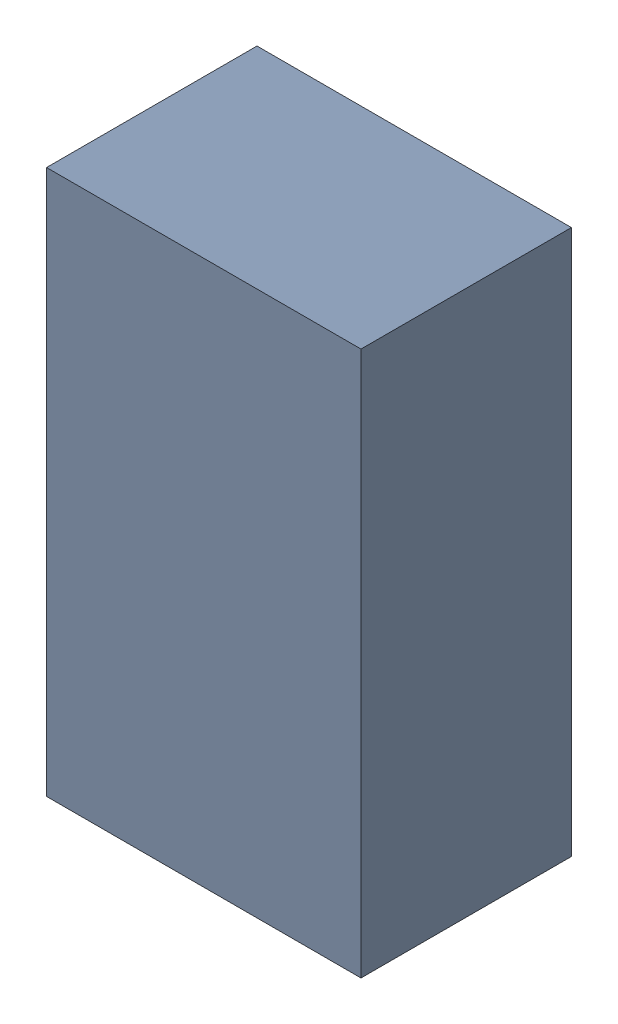
SolidWorks assembly U1Kanaloa_v2.0.0_Motor, configuration Default. Lengths in mm.
Overall size (1.27 2.2 0.85).
2 component instances, 1 part files, 0 mates.
Components (placement in the parent):
- 334788272-1: 334788272 [Default] at (45.212 109.474 -3.7524) size (1.27 2.2 0.85)
  - Extruded_16-1: Extruded_16 [Default] at origin size (1.27 2.2 0.85)
